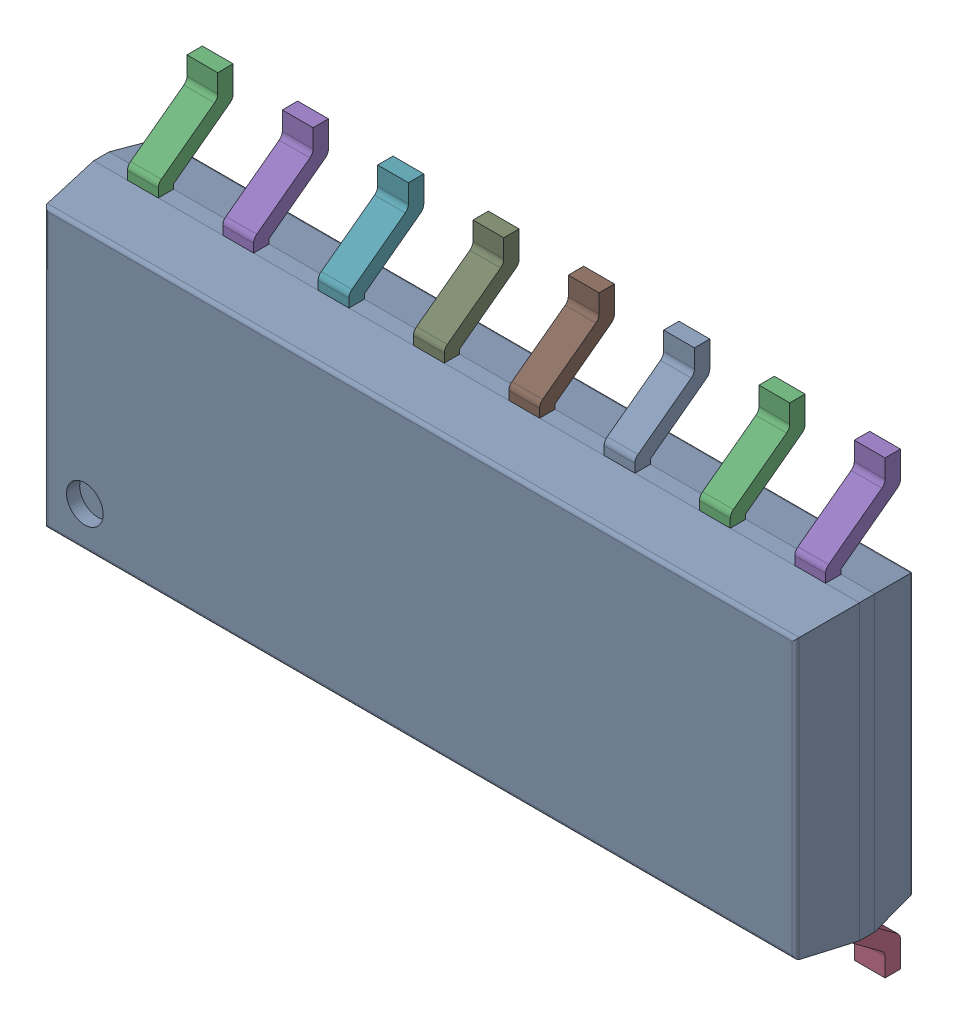
SolidWorks assembly IC17_1.step, configuration Default. Lengths in mm.
Overall size (10.2 6 1.75).
3 component instances, 2 part files, 0 mates.
Components (placement in the parent):
- 6348803008_1.step-11: 6348803008_1.step [Default] at (520.065 262.098 0) x (0 1 0) z (0 0 1) size (6 10.2 1.75)
  - Body-14_1.step-32: Body-14_1.step [Default] at origin size (3.9 10.2 1.57)
  - PinsArrayLR-15_1.step-32: PinsArrayLR-15_1.step [Default] at origin size (6 9.3 1)
